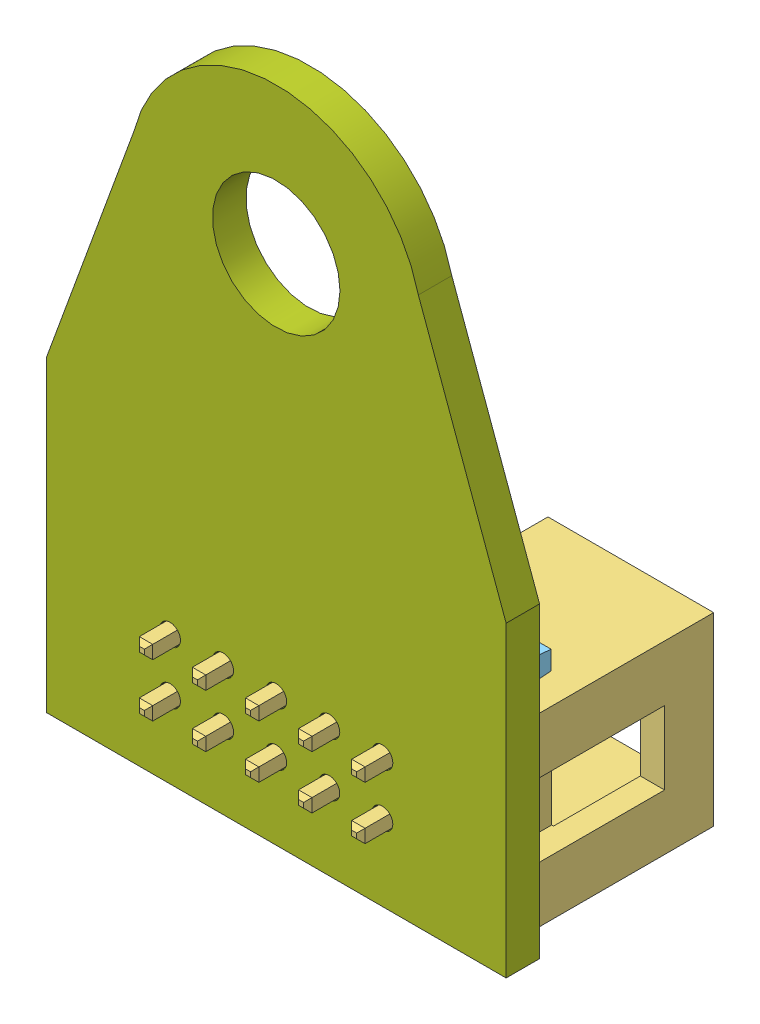
SolidWorks assembly Duet3_accelerometer, configuration Default. Lengths in mm.
Overall size (22 31.51 12.1).
28 component instances, 7 part files, 0 mates.
Components (placement in the parent):
- Duet3_accelerometer.step-1: Duet3_accelerometer.step [Default] at origin size (22 31.51 12.1)
  - C_0402_1005Metric.step-1: C_0402_1005Metric.step [Default] at (13.8 15.1 -0.05) x (1 0 0) z (0 0 -1) size (1 0.5 0.5)
    - SOLID.step-1: SOLID.step [Default] at origin size (1 0.5 0.5)
  - C_0603_1608Metric.step-1: C_0603_1608Metric.step [Default] at (14.7 16.9 -0.05) x (-1 0 0) z (0 0 -1) size (1.6 0.8 0.8)
    - SOLID001.step-1: SOLID001.step [Default] at origin size (1.6 0.8 0.8)
  - IDC-Header_2x05_P2.54mm_Vertical.step-1: IDC-Header_2x05_P2.54mm_Vertical.step [Default] at (5.92 6.2 -0.05) x (0 -1 0) z (0 0 -1) size (9.1 20.36 12.1)
    - SOLID002.step-1: SOLID002.step [Default] at origin size (9.1 20.36 12.1)
  - R_0402_1005Metric.step-1: R_0402_1005Metric.step [Default] at (18.5 10.6 -0.05) x (-1 0 0) z (0 0 -1) size (1 0.5 0.35)
    - SOLID003.step-1: SOLID003.step [Default] at origin size (1 0.5 0.35)
  - R_0402_1005Metric001.step-1: R_0402_1005Metric001.step [Default] at (9.5 10.9 -0.05) x (0 1 0) z (0 0 -1) size (1 0.5 0.35)
    - SOLID003.step-1: SOLID003.step [Default] at origin size (1 0.5 0.35)
  - LED_0603_1608Metric.step-1: LED_0603_1608Metric.step [Default] at (21 11.5 -0.05) x (0 -1 0) z (0 0 -1) size (1.6 0.8 1.1)
    - SOLID005.step-1: SOLID005.step [Default] at origin size (1.6 0.8 1.1)
  - R_0402_1005Metric002.step-1: R_0402_1005Metric002.step [Default] at (7.1 10.9 -0.05) x (0 1 0) z (0 0 -1) size (1 0.5 0.35)
    - SOLID003.step-1: SOLID003.step [Default] at origin size (1 0.5 0.35)
  - R_0402_1005Metric003.step-1: R_0402_1005Metric003.step [Default] at (8.3 10.9 -0.05) x (0 1 0) z (0 0 -1) size (1 0.5 0.35)
    - SOLID003.step-1: SOLID003.step [Default] at origin size (1 0.5 0.35)
  - R_0402_1005Metric004.step-1: R_0402_1005Metric004.step [Default] at (7.4 15.7 -0.05) x (1 0 0) z (0 0 -1) size (1 0.5 0.35)
    - SOLID003.step-1: SOLID003.step [Default] at origin size (1 0.5 0.35)
  - C_0402_1005Metric001.step-1: C_0402_1005Metric001.step [Default] at (7.4 17.1 -0.05) x (-1 0 0) z (0 0 -1) size (1 0.5 0.5)
    - SOLID.step-1: SOLID.step [Default] at origin size (1 0.5 0.5)
  - LGA-16_3x3mm_P0.5mm_LayoutBorder3x5y.step-1: LGA-16_3x3mm_P0.5mm_LayoutBorder3x5y.step [Default] at (11 14.5 -0.05) x (0 1 0) z (0 0 -1) size (3 3 1.03)
    - SOLID010.step-1: SOLID010.step [Default] at origin size (3 3 1.03)
  - R_0402_1005Metric005.step-1: R_0402_1005Metric005.step [Default] at (11.5 10.9 -0.05) x (0 1 0) z (0 0 -1) size (1 0.5 0.35)
    - SOLID003.step-1: SOLID003.step [Default] at origin size (1 0.5 0.35)
  - C_0402_1005Metric002.step-1: C_0402_1005Metric002.step [Default] at (7.1 13.7 -0.05) x (0 -1 0) z (0 0 -1) size (1 0.5 0.5)
    - SOLID.step-1: SOLID.step [Default] at origin size (1 0.5 0.5)
  - Duet3_accelerometer PCB.step-1: Duet3_accelerometer PCB.step [Default] at origin size (22 31.51 1.6)
